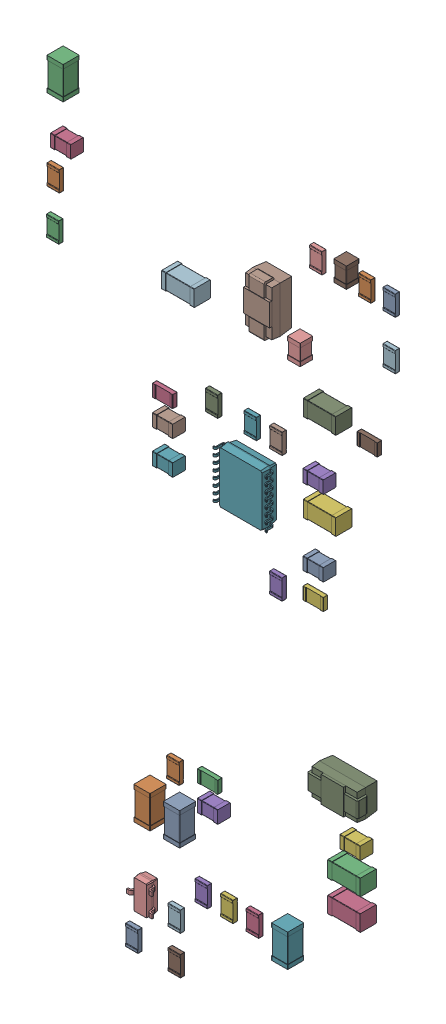
SolidWorks assembly Bot, configuration 默认. Lengths in mm.
Overall size (34.4 72.3 2.22).
43 component instances, 43 part files, 0 mates.
Components (placement in the parent):
- C5_C_0805_2012Metric_5E97372B-1: C5_C_0805_2012Metric_5E97372B [默认] at (76.411 51.91 -1.6) x (1 0 0) z (0 0 -1) size (2 1.25 1.25)
- R15_R_0805_2012Metric_5E973B05-1: R15_R_0805_2012Metric_5E973B05 [默认] at (81.491 78.453 -1.6) x (0 1 0) z (0 0 -1) size (2 1.2 0.45)
- C1_C_1206_3216Metric_5E9736E7-1: C1_C_1206_3216Metric_5E9736E7 [默认] at (50.95 81.1 -1.6) x (0 1 0) z (0 0 -1) size (3.2 1.6 1.6)
- C2_C_0805_2012Metric_5E9736F8-1: C2_C_0805_2012Metric_5E9736F8 [默认] at (51.5 75.6 -1.6) x (-1 0 0) z (0 0 -1) size (2 1.25 1.25)
- C3_C_0805_2012Metric_5E973709-1: C3_C_0805_2012Metric_5E973709 [默认] at (76.411 59.403 -1.6) x (-1 0 0) z (0 0 -1) size (2 1.25 1.25)
- C4_C_1206_3216Metric_5E97BBAC-1: C4_C_1206_3216Metric_5E97BBAC [默认] at (77.046 56.609 -1.6) x (-1 0 0) z (0 0 -1) size (3.2 1.6 1.6)
- C6_C_0805_2012Metric_5E97B6B1-1: C6_C_0805_2012Metric_5E97B6B1 [默认] at (61.552 53.434 -1.6) x (-1 0 0) z (0 0 -1) size (2 1.25 1.25)
- C7_C_0805_2012Metric_5E97374D-1: C7_C_0805_2012Metric_5E97374D [默认] at (61.552 56.736 -1.6) x (1 0 0) z (0 0 -1) size (2 1.25 1.25)
- C8_C_1206_3216Metric_5E97375E-1: C8_C_1206_3216Metric_5E97375E [默认] at (77.046 65.245 -1.6) x (1 0 0) z (0 0 -1) size (3.2 1.6 1.6)
- C9_C_0805_2012Metric_5E97376F-1: C9_C_0805_2012Metric_5E97376F [默认] at (74.506 69.563 -1.6) x (0 -1 0) z (0 0 -1) size (2 1.25 1.25)
- C10_C_0805_2012Metric_5E973780-1: C10_C_0805_2012Metric_5E973780 [默认] at (79.078 78.453 -1.6) x (0 1 0) z (0 0 -1) size (2 1.25 1.25)
- C11_C_1206_3216Metric_5E973791-1: C11_C_1206_3216Metric_5E973791 [默认] at (63.076 69.182 -1.6) x (1 0 0) z (0 0 -1) size (3.2 1.6 1.6)
- C12_C_1206_3216Metric_5E977737-1: C12_C_1206_3216Metric_5E977737 [默认] at (62.441 23.081 -1.6) x (0 1 0) z (0 0 -1) size (3.2 1.6 1.6)
- C13_C_1206_3216Metric_5E978263-1: C13_C_1206_3216Metric_5E978263 [默认] at (59.52 23.081 -1.6) x (0 1 0) z (0 0 -1) size (3.2 1.6 1.6)
- C14_C_1206_3216Metric_5E9737C4-1: C14_C_1206_3216Metric_5E9737C4 [默认] at (79.459 27.018 -1.6) x (-1 0 0) z (0 0 -1) size (3.2 1.6 1.6)
- C15_C_1206_3216Metric_5E9737D5-1: C15_C_1206_3216Metric_5E9737D5 [默认] at (79.459 23.97 -1.6) x (-1 0 0) z (0 0 -1) size (3.2 1.6 1.6)
- C16_C_0805_2012Metric_5E9737E6-1: C16_C_0805_2012Metric_5E9737E6 [默认] at (65.997 26.002 -1.6) x (-1 0 0) z (0 0 -1) size (2 1.25 1.25)
- C17_C_0805_2012Metric_5E9737F7-1: C17_C_0805_2012Metric_5E9737F7 [默认] at (80.059 29.939 -1.6) x (-1 0 0) z (0 0 -1) size (2 1.25 1.25)
- C18_C_1206_3216Metric_5E973808-1: C18_C_1206_3216Metric_5E973808 [默认] at (73.109 18.036 -1.6) x (0 -1 0) z (0 0 -1) size (3.2 1.6 1.6)
- D2_D_SMA_5E9BCED4-1: D2_D_SMA_5E9BCED4 [默认] at (70.823 71.468 -1.6) x (0 -1 0) z (0 0 -1) size (5 2.7 2.22)
- D4_D_SMA_5E9777E8-1: D4_D_SMA_5E9777E8 [默认] at (78.316 33.495 -1.6) x (-1 0 0) z (0 0 -1) size (5 2.7 2.22)
- Q1_SOT_23_5E99EF72-1: Q1_SOT_23_5E99EF72 [默认] at (59.266 15.207 -1.6) x (-1 0 0) z (0 0 -1) size (2.5 3 1.2)
- R1_R_0805_2012Metric_5E973A17-1: R1_R_0805_2012Metric_5E973A17 [默认] at (62.695 11.397 -1.6) x (0 1 0) z (0 0 -1) size (2 1.2 0.45)
- R2_R_0805_2012Metric_5E973A28-1: R2_R_0805_2012Metric_5E973A28 [默认] at (62.695 15.207 -1.6) x (0 1 0) z (0 0 -1) size (2 1.2 0.45)
- R3_R_0805_2012Metric_5E973A39-1: R3_R_0805_2012Metric_5E973A39 [默认] at (58.504 11.397 -1.6) x (0 -1 0) z (0 0 -1) size (2 1.2 0.45)
- R5_R_0805_2012Metric_5E973A5B-1: R5_R_0805_2012Metric_5E973A5B [默认] at (50.75 72.5 -1.6) x (0 1 0) z (0 0 -1) size (2 1.2 0.45)
- R6_R_0805_2012Metric_5E973A6C-1: R6_R_0805_2012Metric_5E973A6C [默认] at (50.7 68.1 -1.6) x (0 1 0) z (0 0 -1) size (2 1.2 0.45)
- R7_R_0805_2012Metric_5E973A7D-1: R7_R_0805_2012Metric_5E973A7D [默认] at (61.552 59.276 -1.6) x (1 0 0) z (0 0 -1) size (2 1.2 0.45)
- R8_R_0805_2012Metric_5E973A8E-1: R8_R_0805_2012Metric_5E973A8E [默认] at (72.728 48.608 -1.6) x (0 1 0) z (0 0 -1) size (2 1.2 0.45)
- R9_R_0805_2012Metric_5E97BAD9-1: R9_R_0805_2012Metric_5E97BAD9 [默认] at (76.411 49.37 -1.6) x (-1 0 0) z (0 0 -1) size (2 1.2 0.45)
- R10_R_0805_2012Metric_5E973AB0-1: R10_R_0805_2012Metric_5E973AB0 [默认] at (70.188 61.054 -1.6) x (0 -1 0) z (0 0 -1) size (2 1.2 0.45)
- R11_R_0805_2012Metric_5E973AC1-1: R11_R_0805_2012Metric_5E973AC1 [默认] at (72.728 61.054 -1.6) x (0 1 0) z (0 0 -1) size (2 1.2 0.45)
- R12_R_0805_2012Metric_5E97B756-1: R12_R_0805_2012Metric_5E97B756 [默认] at (66.378 61.054 -1.6) x (0 1 0) z (0 0 -1) size (2 1.2 0.45)
- R13_R_0805_2012Metric_5E973AE3-1: R13_R_0805_2012Metric_5E973AE3 [默认] at (76.665 78.453 -1.6) x (0 1 0) z (0 0 -1) size (2 1.2 0.45)
- R14_R_0805_2012Metric_5E973AF4-1: R14_R_0805_2012Metric_5E973AF4 [默认] at (81.745 65.245 -1.6) x (1 0 0) z (0 0 -1) size (2 1.2 0.45)
- R16_R_0805_2012Metric_5E973B16-1: R16_R_0805_2012Metric_5E973B16 [默认] at (83.904 73.627 -1.6) x (0 1 0) z (0 0 -1) size (2 1.2 0.45)
- R17_R_0805_2012Metric_5E973B27-1: R17_R_0805_2012Metric_5E973B27 [默认] at (83.904 78.453 -1.6) x (0 -1 0) z (0 0 -1) size (2 1.2 0.45)
- R19_R_0805_2012Metric_5E973B49-1: R19_R_0805_2012Metric_5E973B49 [默认] at (62.568 27.78 -1.6) x (0 -1 0) z (0 0 -1) size (2 1.2 0.45)
- R20_R_0805_2012Metric_5E973B5A-1: R20_R_0805_2012Metric_5E973B5A [默认] at (65.997 28.542 -1.6) x (1 0 0) z (0 0 -1) size (2 1.2 0.45)
- R22_R_0805_2012Metric_5E973B7C-1: R22_R_0805_2012Metric_5E973B7C [默认] at (70.4133 18.636 -1.6) x (0 -1 0) z (0 0 -1) size (2 1.2 0.45)
- R23_R_0805_2012Metric_5E9785CC-1: R23_R_0805_2012Metric_5E9785CC [默认] at (65.362 18.636 -1.6) x (0 -1 0) z (0 0 -1) size (2 1.2 0.45)
- R24_R_0805_2012Metric_5E973B9E-1: R24_R_0805_2012Metric_5E973B9E [默认] at (67.8877 18.636 -1.6) x (0 -1 0) z (0 0 -1) size (2 1.2 0.45)
- U1_TSSOP_16_1EP_44x5mm_Pitch065mm_EP34x5mm_5E973BE1-1: U1_TSSOP_16_1EP_44x5mm_Pitch065mm_EP34x5mm_5E973BE1 [默认] at (69.172 55.085 -1.6) x (1 0 0) z (0 0 -1) size (5.3 5.3 1.6)
